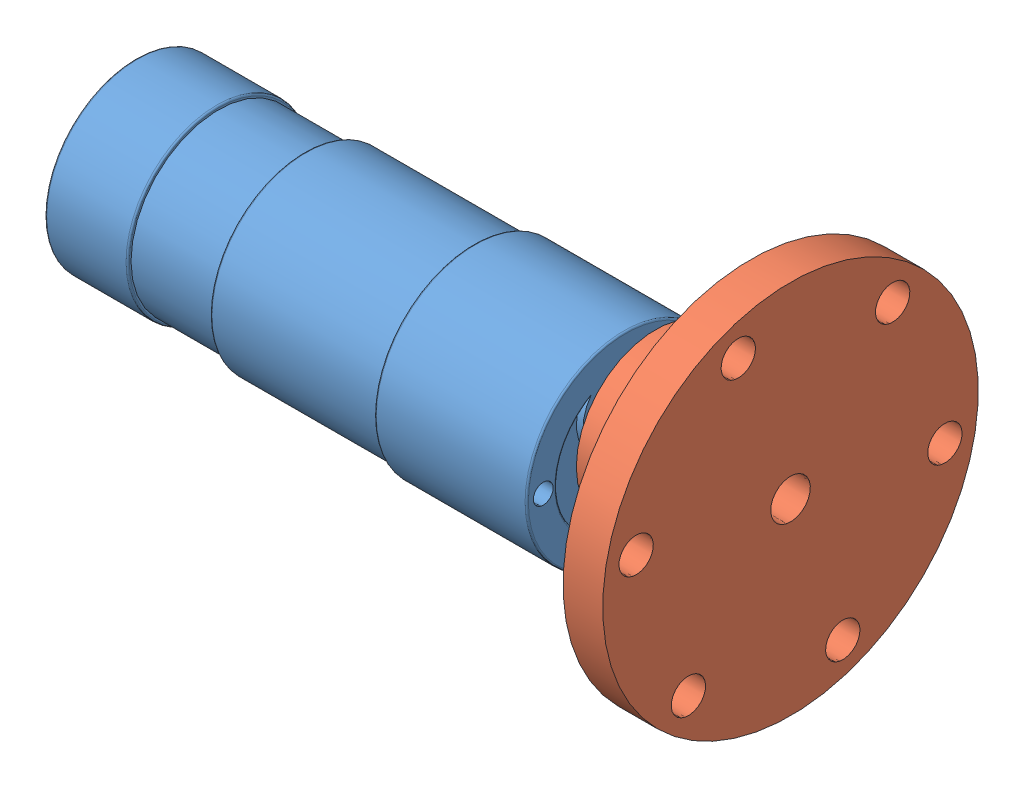
SolidWorks assembly Drivetrain Right Assem, configuration Default. Lengths in mm.
Overall size (99 66.25 66.25).
2 component instances, 2 part files, 2 mates.
Components (placement in the parent):
- Devantech EMG30-1: Devantech EMG30 [Default] at (-103.7925 14.0553 22.3721) size (86.6 30 30)
- Wheel Hub-1: Wheel Hub [Default] at (-4.7925 19.5553 22.3721) x (0 0.183359 0.983046) z (-1 0 0) size (56.8 56.8 22.4)
Mates (geometry in assembly coordinates):
- Concentric1: concentric: cylinder of Devantech EMG30-1 through (-17.1925 19.5553 22.3721) axis (-1 0 0) radius 2.5; cylinder of Wheel Hub-1 through (11.325 19.5553 22.3721) axis (-1 0 0) radius 3
- Coincident2: coincident anti-aligned: plane of Devantech EMG30-1 through (-27.1925 14.0553 22.3721) normal (1 0 0); plane of Wheel Hub-1 through (-27.1925 19.5553 22.3721) normal (-1 0 0)
